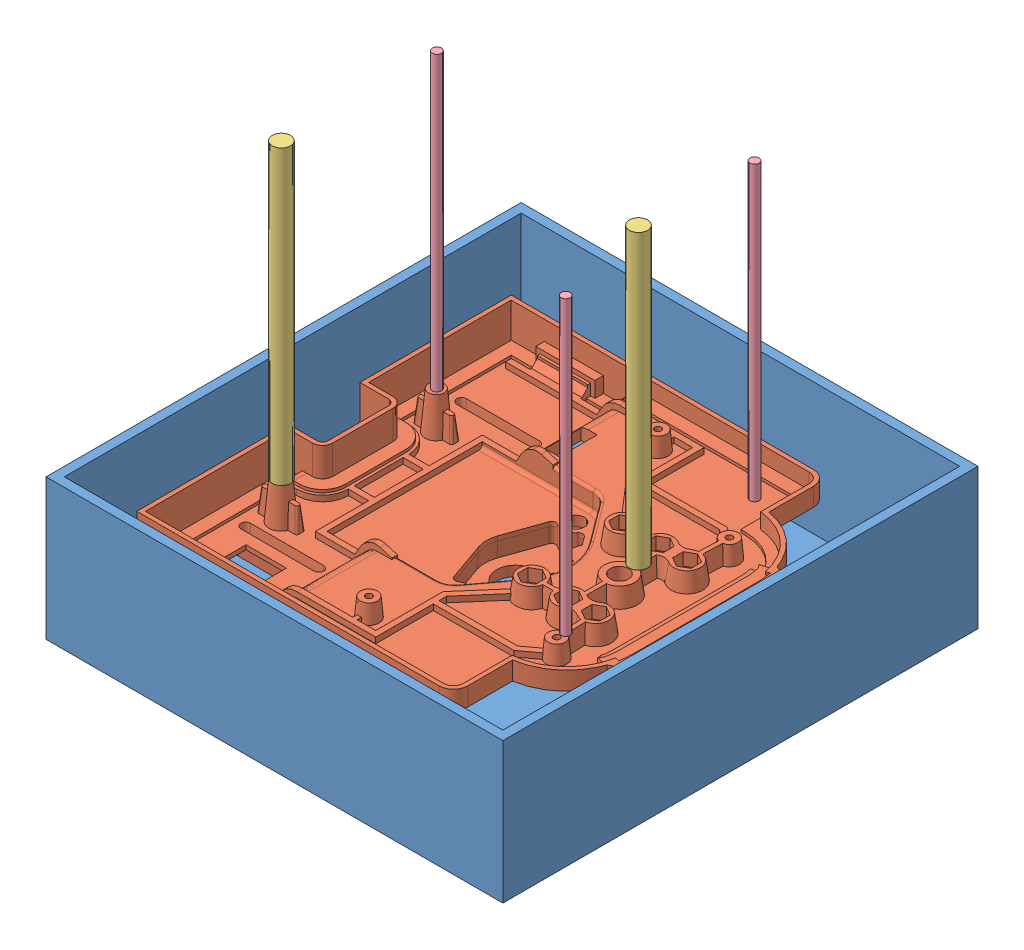
SolidWorks assembly MOLD, CHASSIS, REAR COVER, configuration Default. Lengths in mm.
Overall size (158.75 138.41 165.1).
7 component instances, 4 part files, 8 mates.
Components (placement in the parent):
- MOLD, CHASSIS, REAR COVER-1: MOLD, CHASSIS, REAR COVER [Default] at (-137.9745 -18.3902 66.2589) size (158.75 48.9 165.1)
- MOLD, CHASSIS, REAR UNIBODY COVER, Support-1: MOLD, CHASSIS, REAR UNIBODY COVER, Support [Default] at (-185.2321 18.4208 34.6701) x (0 0 -1) z (-1 0 0) size (130.12 23.59 130.65)
- MOLD, POURING SPRUE-1: MOLD, POURING SPRUE [Default] at (-100.6466 18.4208 59.6338) size (6.35 101.6 6.35)
- MOLD, POURING SPRUE-2: MOLD, POURING SPRUE [Default] at (-188.1229 18.4208 96.2385) size (6.35 101.6 6.35)
- MOLD, POURING VENT-1: MOLD, POURING VENT [Default] at (-92.2271 18.4208 93.3381) size (3.17 101.6 3.17)
- MOLD, POURING VENT-2: MOLD, POURING VENT [Default] at (-106.2713 12.0708 13.6927) size (3.17 101.6 3.17)
- MOLD, POURING VENT-3: MOLD, POURING VENT [Default] at (-188.1856 18.4208 42.1618) size (3.17 101.6 3.17)
Mates (geometry in assembly coordinates):
- Distance1: distance = 12.7 mm anti-aligned: plane of MOLD, CHASSIS, REAR UNIBODY COVER, Support-1 through (-167.5995 -2.5152 103.7589) normal (0 -1 0); plane of MOLD, CHASSIS, REAR COVER-1 through (-58.5995 -15.2152 -16.2911) normal (0 1 0)
- Width1: width anti-aligned: plane of MOLD, CHASSIS, REAR UNIBODY COVER, Support-1 through (-203.2995 6.3348 83.7589) normal (-1 0 0); plane of MOLD, CHASSIS, REAR UNIBODY COVER, Support-1 through (-72.6495 17.4396 88.4839) normal (1 0 0); plane of MOLD, CHASSIS, REAR COVER-1 through (-214.1745 30.5048 -13.1161) normal (1 0 0); plane of MOLD, CHASSIS, REAR COVER-1 through (-61.7745 30.5048 145.6339) normal (-1 0 0)
- Width2: width aligned: plane of MOLD, CHASSIS, REAR UNIBODY COVER, Support-1 through (-198.2995 6.3348 1.1989) normal (0 0 -1); plane of MOLD, CHASSIS, REAR UNIBODY COVER, Support-1 through (-198.2995 6.3348 131.3189) normal (0 0 1); plane of MOLD, CHASSIS, REAR COVER-1 through (-214.1745 30.5048 145.6339) normal (0 0 -1); plane of MOLD, CHASSIS, REAR COVER-1 through (-61.7745 30.5048 -13.1161) normal (0 0 1)
- Coincident1: coincident anti-aligned: plane of MOLD, CHASSIS, REAR UNIBODY COVER, Support-1 through (-97.7845 18.4208 75.0934) normal (0 1 0); plane of MOLD, POURING SPRUE-1 through (-100.6466 18.4208 59.6338) normal (0 -1 0)
- Coincident2: coincident anti-aligned: plane of MOLD, CHASSIS, REAR UNIBODY COVER, Support-1 through (-188.2692 18.4208 42.2589) normal (0 1 0); plane of MOLD, POURING SPRUE-2 through (-188.1229 18.4208 96.2385) normal (0 -1 0)
- Coincident3: coincident anti-aligned: plane of MOLD, CHASSIS, REAR UNIBODY COVER, Support-1 through (-137.465 18.4208 116.4886) normal (0 1 0); plane of MOLD, POURING VENT-1 through (-92.2271 18.4208 93.3381) normal (0 -1 0)
- Coincident4: coincident anti-aligned: plane of MOLD, CHASSIS, REAR UNIBODY COVER, Support-1 through (-77.6495 12.0708 6.1989) normal (0 1 0); plane of MOLD, POURING VENT-2 through (-106.2713 12.0708 13.6927) normal (0 -1 0)
- Coincident5: coincident anti-aligned: plane of MOLD, CHASSIS, REAR UNIBODY COVER, Support-1 through (-188.2692 18.4208 42.2589) normal (0 1 0); plane of MOLD, POURING VENT-3 through (-188.1856 18.4208 42.1618) normal (0 -1 0)
